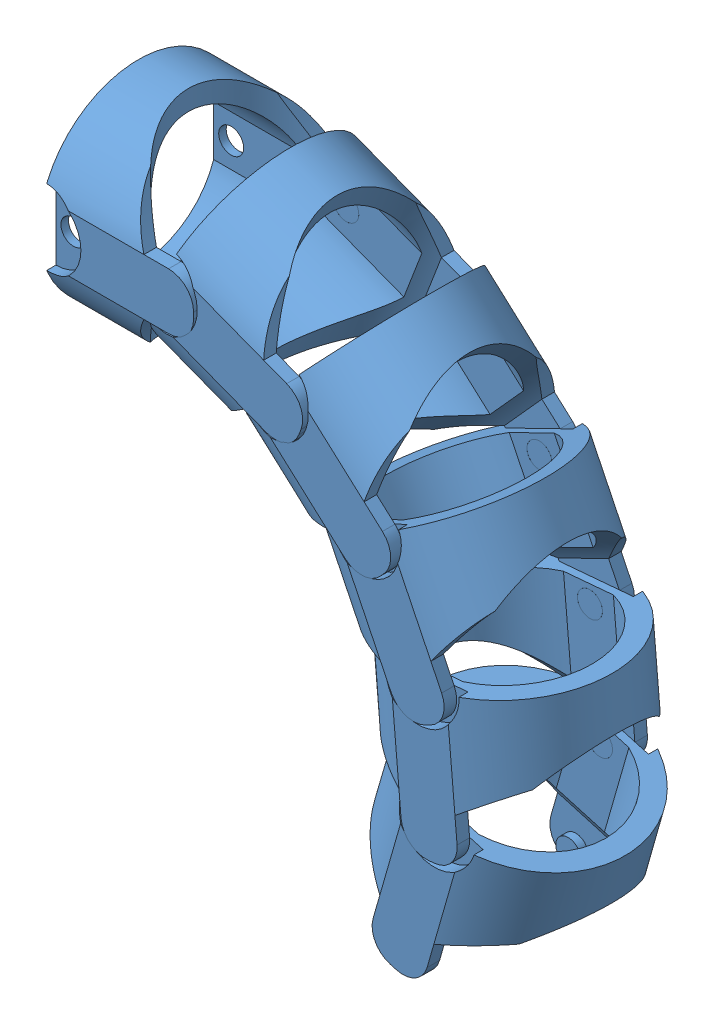
SolidWorks assembly wydłużenie narzędzia+wiązania, configuration Domyślna. Lengths in mm.
Overall size (6.8 8.26 2.72).
6 component instances, 1 part files, 5 mates.
Components (placement in the parent):
- zginacz v2-1: zginacz v2 [Domyślna] at (-2.5375 -0.0643 2.7736) size (2.1 2.77 2.72)
- zginacz v2-2: zginacz v2 [Domyślna] at (-0.8277 0.4743 2.7736) x (0.93358 -0.358368 0) z (0 0 1) size (2.1 2.77 2.72)
- zginacz v2-3: zginacz v2 [Domyślna] at (0.9616 0.3645 2.7736) x (0.743145 -0.669131 0) z (0 0 1) size (2.1 2.77 2.72)
- zginacz v2-4: zginacz v2 [Domyślna] at (2.6162 -0.3676 2.7736) x (0.438371 -0.898794 0) z (0 0 1) size (2.1 2.77 2.72)
- zginacz v2-9: zginacz v2 [Domyślna] at (3.8499 -1.6683 2.7736) x (0.087156 -0.996195 0) z (0 0 1) size (2.1 2.77 2.72)
- zginacz v2-10: zginacz v2 [Domyślna] at (4.5355 -3.3247 2.7736) x (-0.275637 -0.961262 0) z (0 0 1) size (2.1 2.77 2.72)
Mates (geometry in assembly coordinates):
- Zawias1: hinge = 1.937315 rad anti-aligned: cylinder of zginacz v2-1 through (0.5756 -0.0643 3.8236) axis (0 0 1) radius 0.175; cylinder of zginacz v2-2 through (0.5756 -0.0643 1.4436) axis (0 0 1) radius 0.175; plane of zginacz v2-2 through (0.3469 0.0235 3.9286) normal (0 0 1); plane of zginacz v2-1 through (-1.2794 -0.0643 3.9286) normal (0 0 -1); plane of zginacz v2-1 through (-1.2794 -0.4572 3.9286) normal (0 -1 0); plane of zginacz v2-2 through (0.3469 0.0235 2.7736) normal (-0.93358 0.358368 0)
- Zawias3: hinge = 1.937315 rad anti-aligned: cylinder of zginacz v2-3 through (2.0787 -0.6413 1.4436) axis (0 0 1) radius 0.175; cylinder of zginacz v2-2 through (2.0787 -0.6413 3.8236) axis (0 0 1) radius 0.175; plane of zginacz v2-3 through (1.8966 -0.4774 3.9286) normal (0 0 1); plane of zginacz v2-2 through (0.3469 0.0235 3.9286) normal (0 0 -1); plane of zginacz v2-2 through (0.2061 -0.3433 3.9286) normal (-0.358368 -0.93358 0); plane of zginacz v2-3 through (1.8966 -0.4774 2.7736) normal (-0.743145 0.669131 0)
- Zawias4: hinge = 1.186824 rad anti-aligned: cylinder of zginacz v2-4 through (3.2751 -1.7186 1.4436) axis (0 0 1) radius 0.175; cylinder of zginacz v2-3 through (3.2751 -1.7186 3.8236) axis (0 0 1) radius 0.175; plane of zginacz v2-4 through (3.1677 -1.4984 3.9286) normal (0 0 1); plane of zginacz v2-3 through (1.8966 -0.4774 3.9286) normal (0 0 -1); plane of zginacz v2-3 through (3.72 -1.5906 3.9286) normal (0.669131 0.743145 0); plane of zginacz v2-4 through (3.1677 -1.4984 2.7736) normal (-0.438371 0.898794 0)
- Zawias9: hinge = 1.937315 rad anti-aligned: cylinder of zginacz v2-9 through (3.9809 -3.1657 1.4436) axis (0 0 1) radius 0.175; cylinder of zginacz v2-4 through (3.9809 -3.1657 3.8236) axis (0 0 1) radius 0.175; plane of zginacz v2-4 through (3.1677 -1.4984 3.9286) normal (0 0 -1); plane of zginacz v2-9 through (3.9595 -2.9216 3.9286) normal (0 0 1); plane of zginacz v2-4 through (2.8147 -1.6706 3.9286) normal (-0.898794 -0.438371 0); plane of zginacz v2-9 through (3.9595 -2.9216 2.7736) normal (-0.087156 0.996195 0)
- Zawias11: hinge = 1.937315 rad anti-aligned: cylinder of zginacz v2-9 through (4.1212 -4.7696 3.8236) axis (0 0 1) radius 0.175; cylinder of zginacz v2-10 through (4.1212 -4.7696 1.4436) axis (0 0 1) radius 0.175; plane of zginacz v2-10 through (4.1887 -4.534 3.9286) normal (0 0 1); plane of zginacz v2-9 through (3.9595 -2.9216 3.9286) normal (0 0 -1); plane of zginacz v2-10 through (4.1887 -4.534 2.7736) normal (0.275637 0.961262 0); plane of zginacz v2-9 through (3.5682 -2.9558 3.9286) normal (-0.996195 -0.087156 0)
